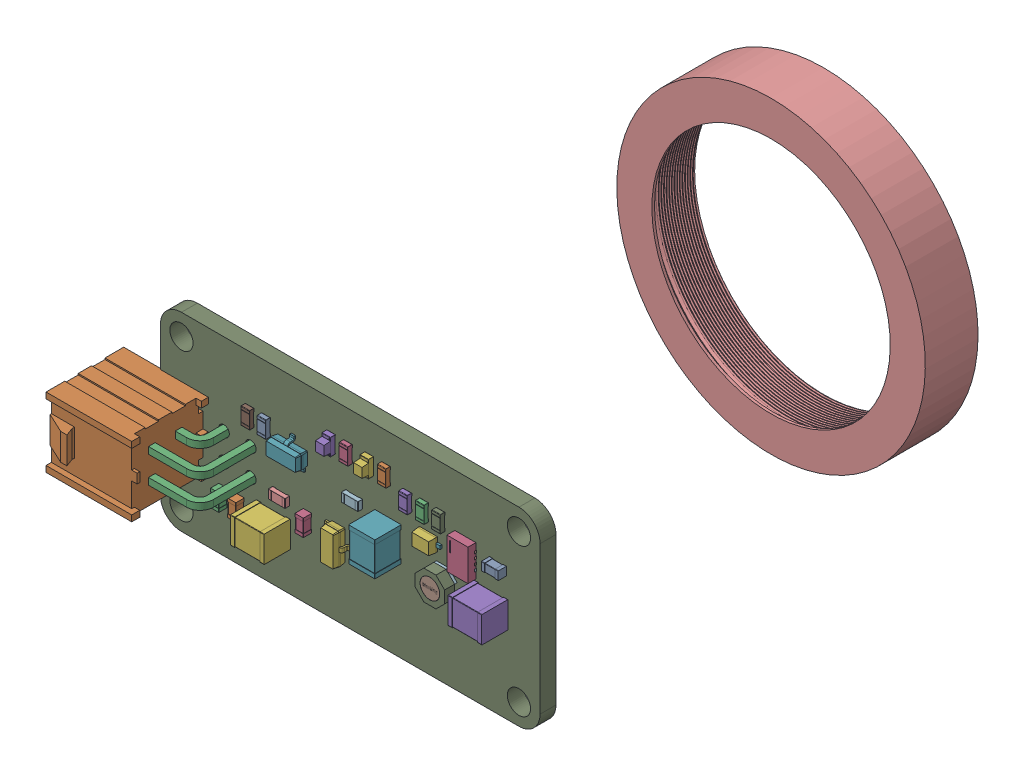
SolidWorks assembly UV_LED_Case_CS-mount, configuration Default. Lengths in mm.
Overall size (42.26 41.36 52.78).
2 component instances, 2 part files, 1 mates.
Components (placement in the parent):
- UV_LED_Pulse-1: UV_LED_Pulse [Default] at origin size (39.58 18 10.93)
- CS to C Mount Adapter-1: CS to C Mount Adapter [Standard] at (0 0 -43.3949) x (-0.712828 -0.701338 0) z (0 0 -1) size (29.25 29.25 5.1)
Mates (geometry in assembly coordinates):
- Concentric1: concentric anti-aligned: circle of UV_LED_Pulse-1; cylinder of CS to C Mount Adapter-1 through (0 0 -43.3949) axis (0 0 1) radius 11.3
